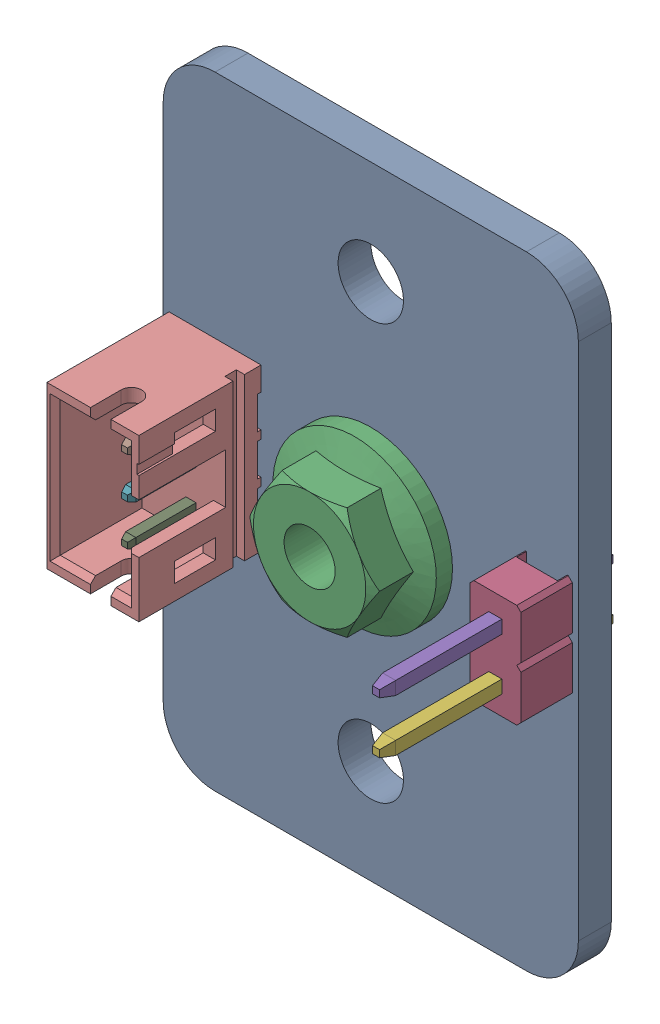
SolidWorks assembly Screw_Switch, configuration Default. Lengths in mm.
Overall size (20.32 30.48 12.96).
5 component instances, 4 part files, 0 mates.
Components (placement in the parent):
- Screw_Switch_BOARD-1: Screw_Switch_BOARD [Default] at origin size (20.32 30.48 1.61)
- Mounting_hole_M3-Footprint-2_CMP-00600-5-1: Mounting_hole_M3-Footprint-2_CMP-00600-5 [Default] at (33.02 40.64 0.0203) x (1 0 0) z (0 0 -1) size (8 8 3)
- Mounting_hole_M3-Footprint-2_CMP-00600-5-2: Mounting_hole_M3-Footprint-2_CMP-00600-5 [Default] at (33.02 40.64 1.5903) x (-1 0 0) z (0 0 1) size (8 8 3)
- 22-28-4020-Footprint-1_CMP-00157-4-1: 22-28-4020-Footprint-1_CMP-00157-4 [Default] at (41.656 41.91 1.5903) x (0 -1 0) z (0 0 1) size (5.08 2.5 11.43)
- JST-B3B-PH-K-S-3_V_CMP-00693-1-1: JST-B3B-PH-K-S-3_V_CMP-00693-1 [Default] at (25.4 40.64 1.5903) x (0 -1 0) z (0 0 1) size (7.9 4.5 9.4)
